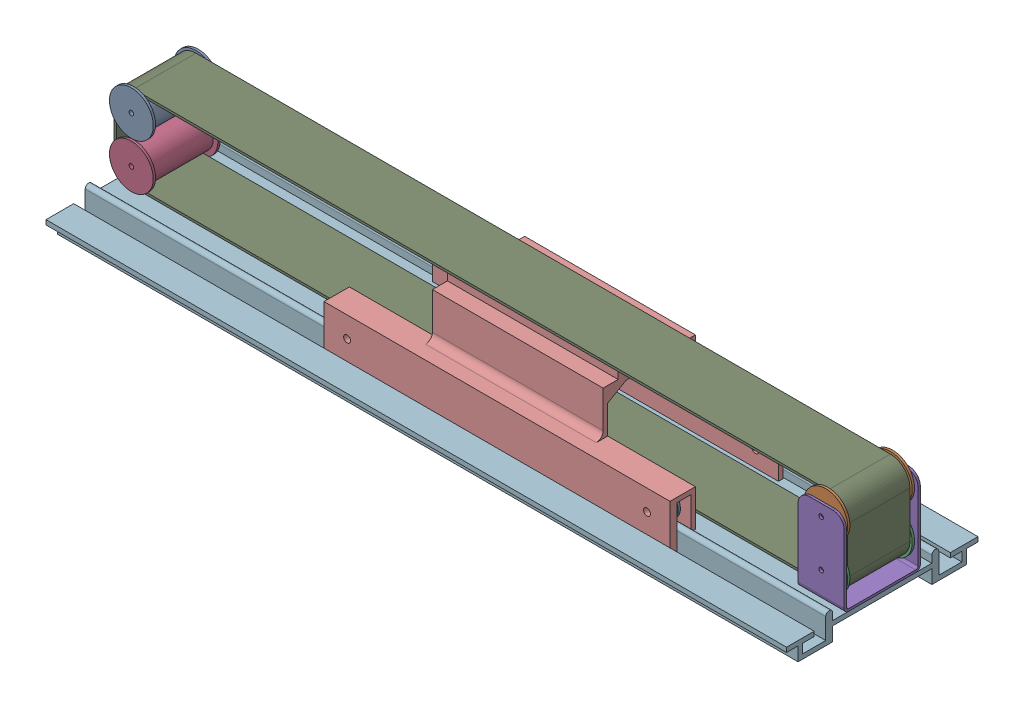
SolidWorks assembly 01_Carrier, configuration Default. Lengths in mm.
Overall size (321 49 83).
12 component instances, 6 part files, 0 mates.
Components (placement in the parent):
- Roller.1.2-1: Roller.1.2 [Default] at (-301 0 0) size (19 19 29)
- Roller.1.2-2: Roller.1.2 [Default] at origin size (19 19 29)
- Roller.1.2-3: Roller.1.2 [Default] at (0 -20 0) size (19 19 29)
- Roller.1.2-4: Roller.1.2 [Default] at (-301 -20 0) size (19 19 29)
- Bracket.2-1: Bracket.2 [Default] at (175 0 0) size (20 36.5 33)
- Wheel.2-1: Wheel.2 [Default] at (118 0 0) size (12 12 5)
- Wheel.2-2: Wheel.2 [Default] at (248 58.6314 -492.1127) x (1 0 0) z (0 0 -1) size (12 12 5)
- Wheel.2-3: Wheel.2 [Default] at (248 58.6314 -538.1127) x (1 0 0) z (0 0 -1) size (12 12 5)
- Belt-1: Belt [Default] at origin size (318 37 27)
- Carrier-1: Carrier [Default] at (258 0 0) size (150 43.5 64)
- Wheel.2-4: Wheel.2 [Default] at (118 0 46) size (12 12 5)
- RailProfile-1: RailProfile [Default] at origin size (321 12.5 83)
